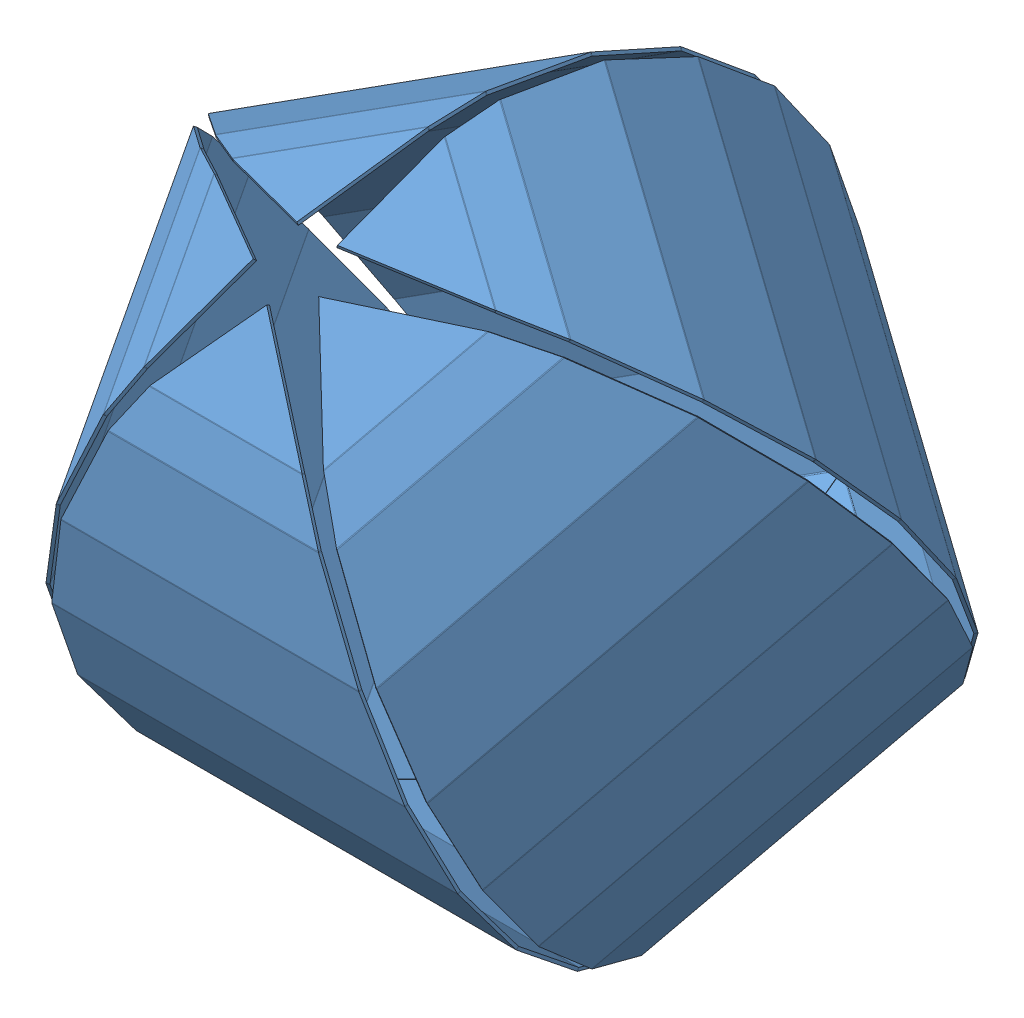
SolidWorks assembly topopen, configuration Default. Lengths in mm.
Overall size (508.08 451.8 444.02).
5 component instances, 1 part files, 0 mates.
Components (placement in the parent):
- shellarcclose-6: shellarcclose [Default] at (-44.6614 -185.4582 385.2511) size (199.55 327.22 257.52)
- shellarcclose-7: shellarcclose [Default] at (414.5319 10.6407 115.344) x (0.309017 0.559017 -0.769421) z (0.769421 0.328582 0.547746) size (199.55 327.22 257.52)
- shellarcclose-8: shellarcclose [Default] at (239.1356 327.9355 -321.3747) x (-0.809017 0.345492 -0.475528) z (0.475528 0.860239 -0.184017) size (199.55 327.22 257.52)
- shellarcclose-9: shellarcclose [Default] at (-328.4585 327.9355 -321.3747) x (-0.809017 -0.345492 0.475528) z (-0.475528 0.860239 -0.184017) size (199.55 327.22 257.52)
- shellarcclose-10: shellarcclose [Default] at (-503.8547 10.6407 115.344) x (0.309017 -0.559017 0.769421) z (-0.769421 0.328582 0.547746) size (199.55 327.22 257.52)
